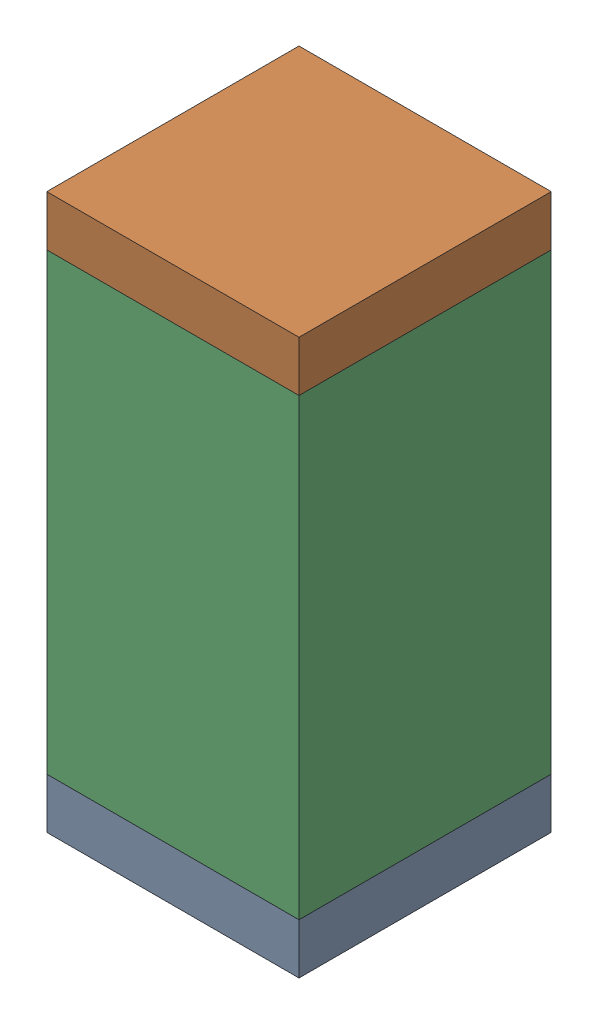
SolidWorks assembly C56, configuration Default. Lengths in mm.
Overall size (0.5 1.1 0.5).
6 component instances, 2 part files, 0 mates.
Components (placement in the parent):
- 810157360-1: 810157360 [Default] at (125.65 48.4 0) size (0.5 0.1 0.5)
  - Extruded_9-1: Extruded_9 [Default] at origin size (0.5 0.1 0.5)
- 810157360-2: 810157360 [Default] at (125.65 49.4 0) size (0.5 0.1 0.5)
  - Extruded_9-1: Extruded_9 [Default] at origin size (0.5 0.1 0.5)
- 791586336-1: 791586336 [Default] at (125.65 48.9 0) size (0.5 0.9 0.5)
  - Extruded_8-1: Extruded_8 [Default] at origin size (0.5 0.9 0.5)
